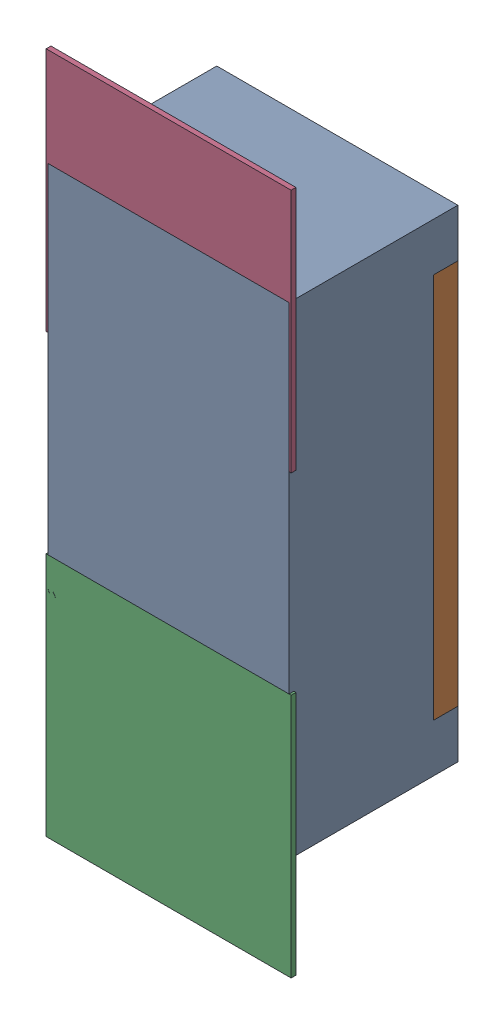
SolidWorks assembly R70, configuration Défaut. Lengths in mm.
Overall size (0.51 1.42 0.35).
5 component instances, 2 part files, 0 mates.
Components (placement in the parent):
- R0402-1: R0402 [Défaut] at (-1.9305 -20.0406 -2.0818) x (0 1 0) z (0 0 -1) size (1 0.5 0.35)
- 6504207776-1: 6504207776 [Défaut] at (-1.9303 -20.4977 -2.0918) size (0.51 0.51 0.01)
  - Extruded-1: Extruded [Défaut] at origin size (0.51 0.51 0.01)
- 6504207776-2: 6504207776 [Défaut] at (-1.9303 -19.5906 -2.0918) size (0.51 0.51 0.01)
  - Extruded-1: Extruded [Défaut] at origin size (0.51 0.51 0.01)
